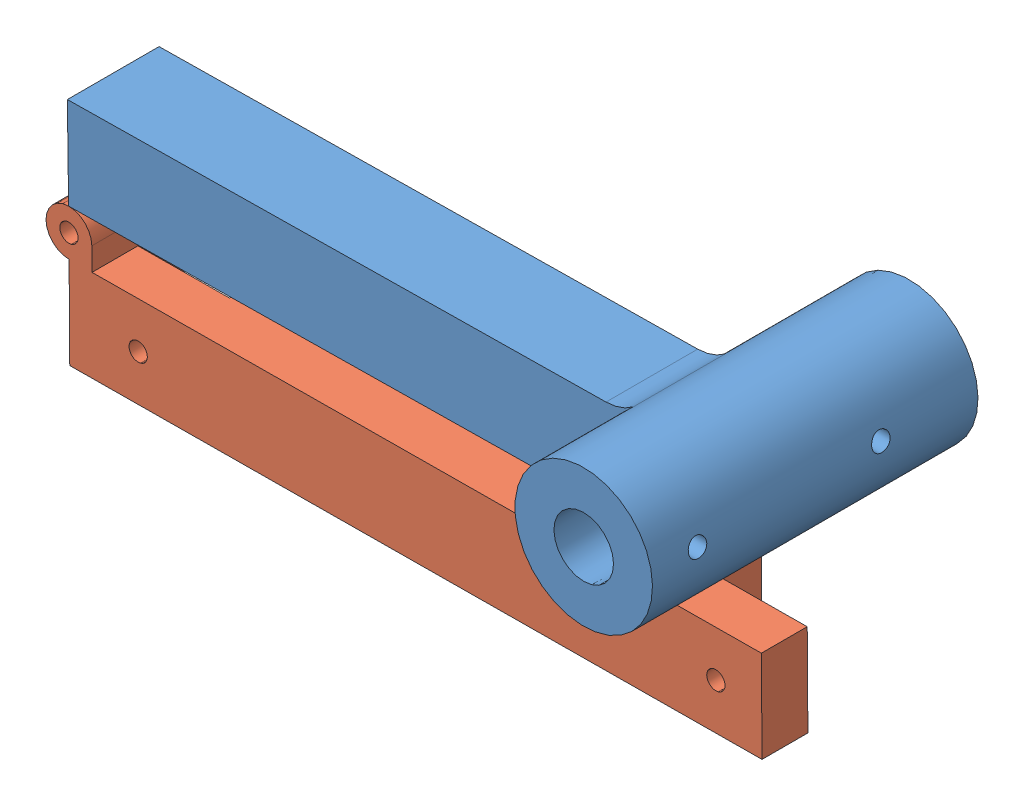
SolidWorks assembly Mirror holder v2 assembly, configuration Default. Lengths in mm.
Overall size (156.59 57.04 71).
2 component instances, 2 part files, 2 mates.
Components (placement in the parent):
- Body1-1: Body1 [Default] at (85.6734 100.2309 116.3237) x (-0.999907 -0.013603 0) z (0 0 1) size (152.5 35 71)
- Body2-1: Body2 [Default] at (96.1956 50.3384 116.3237) x (0.999973 0.00731 0) z (0 0 1) size (156 30 20)
Mates (geometry in assembly coordinates):
- Concentric1: concentric anti-aligned: cylinder of Body1-1 through (91.013 75.3012 126.3237) axis (0 0 -1) radius 2; cylinder of Body2-1 through (91.013 75.3012 120.6668) axis (0 0 1) radius 2
- Coincident1: coincident anti-aligned: plane of Body1-1 through (85.6734 100.2309 126.3237) normal (0 0 1); plane of Body2-1 through (116.3585 28.1245 126.3237) normal (0 0 -1)
